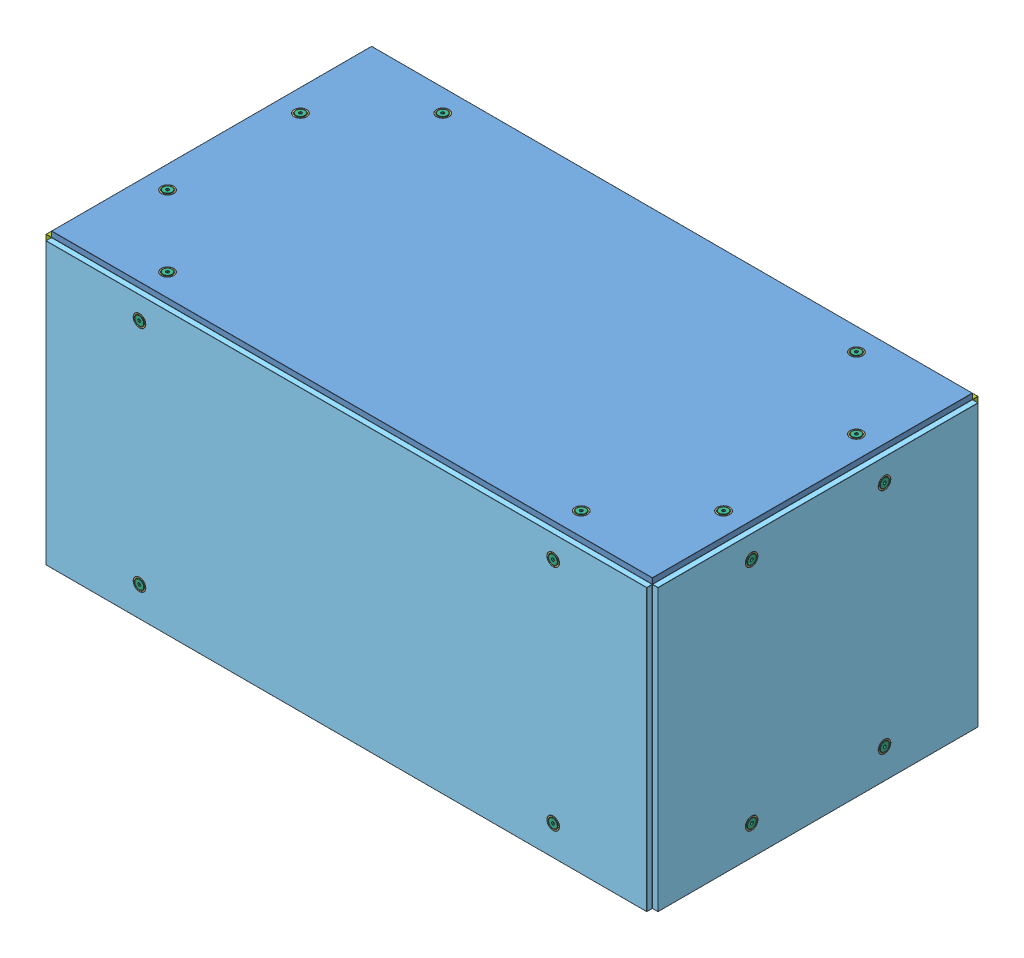
SolidWorks assembly SC.1.GD-VC, configuration Glass Dome 654 x 354 x 300. Lengths in mm.
Overall size (654.53 306.26 354.53).
109 component instances, 7 part files, 60 mates.
Components (placement in the parent):
- SC.1.G.VC.T-1: SC.1.G.VC.T [Topo 642 x 342] at (-2.0067 135.176 -92.8158) size (642 6 342)
- SC.1.L-1: SC.1.L [Default] at (-230.0067 117.676 60.6842) x (0 0 -1) z (1 0 0)
- SC.1.AC2-1: SC.1.AC2 [Default] at (-223.0067 136.176 54.1842) x (0 -1 0) z (0 0 1)
- SC.1.A2-1: SC.1.A2 [Default] at (-223.0067 133.176 54.1842) x (1 0 0) z (0 1 0)
- SC.1.A2-2: SC.1.A2 [Default] at (-223.0067 131.176 54.1842) x (1 0 0) z (0 1 0)
- SC.1.L-2: SC.1.L [Default] at (301.4933 117.676 -14.8158) x (-1 0 0) z (0 0 -1)
- SC.1.AC2-2: SC.1.AC2 [Default] at (294.9933 136.176 -21.8158) x (0 -1 0) z (0 0 1)
- SC.1.A2-3: SC.1.A2 [Default] at (294.9933 131.176 -21.8158) x (1 0 0) z (0 1 0)
- SC.1.A2-4: SC.1.A2 [Default] at (294.9933 133.176 -21.8158) x (1 0 0) z (0 1 0)
- SC.1.AC2-3: SC.1.AC2 [Default] at (218.9933 136.176 54.1842) x (0 -1 0) z (0 0 -1)
- SC.1.A2-5: SC.1.A2 [Default] at (218.9933 135.176 54.1842) x (-1 0 0) z (0 -1 0)
- SC.1.A2-6: SC.1.A2 [Default] at (218.9933 133.176 54.1842) x (-1 0 0) z (0 -1 0)
- SC.1.L-3: SC.1.L [Default] at (211.9933 117.676 60.6842) x (0 0 -1) z (1 0 0)
- SC.1.AC2-4: SC.1.AC2 [Default] at (294.9933 136.176 -163.8158) x (0 -1 0) z (0 0 1)
- SC.1.A2-7: SC.1.A2 [Default] at (294.9933 135.176 -163.8158) x (1 0 0) z (0 -1 0)
- SC.1.A2-8: SC.1.A2 [Default] at (294.9933 133.176 -163.8158) x (1 0 0) z (0 -1 0)
- SC.1.L-4: SC.1.L [Default] at (301.4933 117.676 -156.8158) x (-1 0 0) z (0 0 -1)
- SC.1.AC2-5: SC.1.AC2 [Default] at (-299.0067 136.176 -21.8158) x (0 -1 0) z (0 0 -1)
- SC.1.A2-9: SC.1.A2 [Default] at (-299.0067 135.176 -21.8158) x (-1 0 0) z (0 -1 0)
- SC.1.A2-10: SC.1.A2 [Default] at (-299.0067 133.176 -21.8158) x (-1 0 0) z (0 -1 0)
- SC.1.L-5: SC.1.L [Default] at (-305.5067 117.676 -28.8158)
- SC.1.AC2-6: SC.1.AC2 [Default] at (-299.0067 136.176 -163.8158) x (0 -1 0) z (0 0 -1)
- SC.1.A2-11: SC.1.A2 [Default] at (-299.0067 133.176 -163.8158) x (-1 0 0) z (0 1 0)
- SC.1.A2-12: SC.1.A2 [Default] at (-299.0067 131.176 -163.8158) x (-1 0 0) z (0 1 0)
- SC.1.L-6: SC.1.L [Default] at (-305.5067 117.676 -170.8158)
- SC.1.AC2-7: SC.1.AC2 [Default] at (218.9933 136.176 -239.8158) x (0 -1 0) z (0 0 -1)
- SC.1.A2-13: SC.1.A2 [Default] at (218.9933 133.176 -239.8158) x (-1 0 0) z (0 1 0)
- SC.1.A2-14: SC.1.A2 [Default] at (218.9933 131.176 -239.8158) x (-1 0 0) z (0 1 0)
- SC.1.L-7: SC.1.L [Default] at (225.9933 117.676 -246.3158) x (0 0 1) z (-1 0 0)
- SC.1.AC2-8: SC.1.AC2 [Default] at (-223.0067 136.176 -239.8158) x (0 -1 0) z (0 0 1)
- SC.1.A2-15: SC.1.A2 [Default] at (-223.0067 135.176 -239.8158) x (1 0 0) z (0 -1 0)
- SC.1.A2-16: SC.1.A2 [Default] at (-223.0067 133.176 -239.8158) x (1 0 0) z (0 -1 0)
- SC.1.L-8: SC.1.L [Default] at (-216.0067 117.676 -246.3158) x (0 0 1) z (-1 0 0)
- SC.1.A2-20: SC.1.A2 [Default] at (-223.0067 111.176 74.1842)
- SC.1.A2-21: SC.1.A2 [Default] at (-223.0067 111.176 76.1842)
- SC.1.G.VC.L-1: SC.1.G.VC.L [Lateral 642 x 300] at (-2.0067 -14.824 78.1842)
- SC.1.A2-22: SC.1.A2 [Default] at (316.9933 111.176 -21.8158) x (0 0 -1) z (1 0 0)
- SC.1.A2-23: SC.1.A2 [Default] at (314.9933 111.176 -21.8158) x (0 0 -1) z (1 0 0)
- SC.1.G.VC.L-5: SC.1.G.VC.L [Lateral 342 x 300] at (318.9933 -14.824 -92.8158) x (0 0 -1) z (1 0 0)
- SC.1.AC2-10: SC.1.AC2 [Default] at (-223.0067 111.176 79.1842) x (0 0 -1) z (0 -1 0)
- SC.1.AC2-11: SC.1.AC2 [Default] at (319.9933 111.176 -21.8158) x (-1 0 0) z (0 0 1)
- SC.1.P7991-12-1: SC.1.P7991-12 [ISO 10642 - M5 x 12 --- 12N] at (-223.0067 141.4402 54.1842) x (0 -1 0) z (0 0 1)
- SC.1.P7991-12-17: SC.1.P7991-12 [ISO 10642 - M5 x 12 --- 12N] at (-223.0067 111.176 84.4484) x (0 0 -1) z (0 -1 0)
- SC.1.P7991-12-21: SC.1.P7991-12 [ISO 10642 - M5 x 12 --- 12N] at (294.9933 141.4402 -21.8158) x (0 -1 0) z (0 0 1)
- SC.1.P7991-12-25: SC.1.P7991-12 [ISO 10642 - M5 x 12 --- 12N] at (325.2575 111.176 -21.8158) x (-1 0 0) z (0 0 1)
- SC.1.P7991-12-5: SC.1.P7991-12 [ISO 10642 - M5 x 12 --- 12N] at (218.9933 141.4402 54.1842) x (0 -1 0) z (0 0 -1)
- SC.1.P7991-12-18: SC.1.P7991-12 [ISO 10642 - M5 x 12 --- 12N] at (218.9933 111.176 84.4484) x (0 0 -1) z (0 1 0)
- SC.1.AC2-12: SC.1.AC2 [Default] at (218.9933 111.176 79.1842) x (0 0 -1) z (0 1 0)
- SC.1.A2-24: SC.1.A2 [Default] at (218.9933 111.176 78.1842) x (-1 0 0) z (0 0 -1)
- SC.1.A2-25: SC.1.A2 [Default] at (218.9933 111.176 76.1842) x (-1 0 0) z (0 0 -1)
- SC.1.P7991-12-22: SC.1.P7991-12 [ISO 10642 - M5 x 12 --- 12N] at (294.9933 141.4402 -163.8158) x (0 -1 0) z (0 0 1)
- SC.1.P7991-12-26: SC.1.P7991-12 [ISO 10642 - M5 x 12 --- 12N] at (325.2575 111.176 -163.8158) x (-1 0 0) z (0 0 1)
- SC.1.AC2-13: SC.1.AC2 [Default] at (319.9933 111.176 -163.8158) x (-1 0 0) z (0 0 1)
- SC.1.A2-26: SC.1.A2 [Default] at (318.9933 111.176 -163.8158) x (0 0 1) z (-1 0 0)
- SC.1.A2-27: SC.1.A2 [Default] at (316.9933 111.176 -163.8158) x (0 0 1) z (-1 0 0)
- SC.1.P7991-12-24: SC.1.P7991-12 [ISO 10642 - M5 x 12 --- 12N] at (-299.0067 141.4402 -21.8158) x (0 -1 0) z (0 0 -1)
- SC.1.A2-28: SC.1.A2 [Default] at (-323.0067 111.176 -21.8158) x (0 0 -1) z (1 0 0)
- SC.1.A2-29: SC.1.A2 [Default] at (-321.0067 111.176 -21.8158) x (0 0 -1) z (1 0 0)
- SC.1.AC2-14: SC.1.AC2 [Default] at (-324.0067 111.176 -21.8158) x (1 0 0) z (0 0 -1)
- SC.1.P7991-12-28: SC.1.P7991-12 [ISO 10642 - M5 x 12 --- 12N] at (-329.2709 111.176 -21.8158) x (1 0 0) z (0 0 -1)
- MirrorSC.1.G.VC.L-6: MirrorSC.1.G.VC.L [Lateral 342 x 300] at (-323.0067 -14.824 -92.8158) x (0 0 -1) z (1 0 0)
- SC.1.P7991-12-27: SC.1.P7991-12 [ISO 10642 - M5 x 12 --- 12N] at (-329.2709 111.176 -163.8158) x (1 0 0) z (0 0 -1)
- SC.1.AC2-15: SC.1.AC2 [Default] at (-324.0067 111.176 -163.8158) x (1 0 0) z (0 0 -1)
- SC.1.P7991-12-23: SC.1.P7991-12 [ISO 10642 - M5 x 12 --- 12N] at (-299.0067 141.4402 -163.8158) x (0 -1 0) z (0 0 -1)
- SC.1.P7991-12-20: SC.1.P7991-12 [ISO 10642 - M5 x 12 --- 12N] at (-223.0067 111.176 -270.08) x (0 0 1) z (0 1 0)
- SC.1.AC2-16: SC.1.AC2 [Default] at (-223.0067 111.176 -264.8158) x (0 0 1) z (0 1 0)
- SC.1.A2-30: SC.1.A2 [Default] at (-223.0067 111.176 -263.8158)
- SC.1.A2-31: SC.1.A2 [Default] at (-223.0067 111.176 -261.8158)
- SC.1.P7991-12-16: SC.1.P7991-12 [ISO 10642 - M5 x 12 --- 12N] at (-223.0067 141.4402 -239.8158) x (0 -1 0) z (0 0 1)
- SC.1.P7991-12-15: SC.1.P7991-12 [ISO 10642 - M5 x 12 --- 12N] at (218.9933 141.4402 -239.8158) x (0 -1 0) z (0 0 -1)
- SC.1.A2-32: SC.1.A2 [Default] at (218.9933 111.176 -261.8158) x (-1 0 0) z (0 0 -1)
- SC.1.A2-33: SC.1.A2 [Default] at (218.9933 111.176 -259.8158) x (-1 0 0) z (0 0 -1)
- SC.1.P7991-12-19: SC.1.P7991-12 [ISO 10642 - M5 x 12 --- 12N] at (218.9933 111.176 -270.08) x (0 0 1) z (0 -1 0)
- SC.1.AC2-17: SC.1.AC2 [Default] at (218.9933 111.176 -264.8158) x (0 0 1) z (0 -1 0)
- MirrorSC.1.G.VC.L-7: MirrorSC.1.G.VC.L [Lateral 642 x 300] at (-2.0067 -14.824 -263.8158)
- SC.1.P7991-12-29: SC.1.P7991-12 [ISO 10642 - M5 x 12 --- 12N] at (-223.0067 -132.824 84.4484) x (0 0 -1) z (0 -1 0)
- SC.1.AC2-18: SC.1.AC2 [Default] at (-223.0067 -132.824 79.1842) x (0 0 -1) z (0 -1 0)
- SC.1.A2-34: SC.1.A2 [Default] at (-223.0067 -132.824 74.1842)
- SC.1.A2-35: SC.1.A2 [Default] at (-223.0067 -132.824 76.1842)
- SC.1.P7991-12-33: SC.1.P7991-12 [ISO 10642 - M5 x 12 --- 12N] at (325.2575 -132.824 -21.8158) x (-1 0 0) z (0 0 1)
- SC.1.AC2-19: SC.1.AC2 [Default] at (319.9933 -132.824 -21.8158) x (-1 0 0) z (0 0 1)
- SC.1.A2-36: SC.1.A2 [Default] at (314.9933 -132.824 -21.8158) x (0 -1 0) z (1 0 0)
- SC.1.A2-37: SC.1.A2 [Default] at (316.9933 -132.824 -21.8158) x (0 -1 0) z (1 0 0)
- SC.1.P7991-12-30: SC.1.P7991-12 [ISO 10642 - M5 x 12 --- 12N] at (218.9933 -132.824 84.4484) x (0 0 -1) z (0 1 0)
- SC.1.AC2-20: SC.1.AC2 [Default] at (218.9933 -132.824 79.1842) x (0 0 -1) z (0 1 0)
- SC.1.A2-38: SC.1.A2 [Default] at (218.9933 -132.824 78.1842) x (-1 0 0) z (0 0 -1)
- SC.1.A2-39: SC.1.A2 [Default] at (218.9933 -132.824 76.1842) x (-1 0 0) z (0 0 -1)
- SC.1.P7991-12-34: SC.1.P7991-12 [ISO 10642 - M5 x 12 --- 12N] at (325.2575 -132.824 -163.8158) x (-1 0 0) z (0 0 1)
- SC.1.AC2-21: SC.1.AC2 [Default] at (319.9933 -132.824 -163.8158) x (-1 0 0) z (0 0 1)
- SC.1.A2-40: SC.1.A2 [Default] at (318.9933 -132.824 -163.8158) x (0 -1 0) z (-1 0 0)
- SC.1.A2-41: SC.1.A2 [Default] at (316.9933 -132.824 -163.8158) x (0 -1 0) z (-1 0 0)
- SC.1.P7991-12-36: SC.1.P7991-12 [ISO 10642 - M5 x 12 --- 12N] at (-329.2709 -132.824 -21.8158) x (1 0 0) z (0 0 -1)
- SC.1.AC2-22: SC.1.AC2 [Default] at (-324.0067 -132.824 -21.8158) x (1 0 0) z (0 0 -1)
- SC.1.P7991-12-35: SC.1.P7991-12 [ISO 10642 - M5 x 12 --- 12N] at (-329.2709 -132.824 -163.8158) x (1 0 0) z (0 0 -1)
- SC.1.AC2-23: SC.1.AC2 [Default] at (-324.0067 -132.824 -163.8158) x (1 0 0) z (0 0 -1)
- SC.1.A2-42: SC.1.A2 [Default] at (-321.0067 -132.824 -163.8158) x (0 -1 0) z (-1 0 0)
- SC.1.A2-43: SC.1.A2 [Default] at (-319.0067 -132.824 -163.8158) x (0 -1 0) z (-1 0 0)
- SC.1.A2-44: SC.1.A2 [Default] at (-323.0067 -132.824 -21.8158) x (0 -1 0) z (1 0 0)
- SC.1.A2-45: SC.1.A2 [Default] at (-321.0067 -132.824 -21.8158) x (0 -1 0) z (1 0 0)
- SC.1.A2-46: SC.1.A2 [Default] at (-321.0067 111.176 -163.8158) x (0 0 1) z (-1 0 0)
- SC.1.A2-47: SC.1.A2 [Default] at (-319.0067 111.176 -163.8158) x (0 0 1) z (-1 0 0)
- SC.1.AC2-24: SC.1.AC2 [Default] at (-223.0067 -132.824 -264.8158) x (0 0 1) z (0 1 0)
- SC.1.A2-48: SC.1.A2 [Default] at (-223.0067 -132.824 -263.8158)
- SC.1.A2-49: SC.1.A2 [Default] at (-223.0067 -132.824 -261.8158)
- SC.1.P7991-12-32: SC.1.P7991-12 [ISO 10642 - M5 x 12 --- 12N] at (-223.0067 -132.824 -270.08) x (0 0 1) z (0 1 0)
- SC.1.AC2-25: SC.1.AC2 [Default] at (218.9933 -132.824 -264.8158) x (0 0 1) z (0 -1 0)
- SC.1.A2-50: SC.1.A2 [Default] at (218.9933 -132.824 -261.8158) x (-1 0 0) z (0 0 -1)
- SC.1.A2-51: SC.1.A2 [Default] at (218.9933 -132.824 -259.8158) x (-1 0 0) z (0 0 -1)
- SC.1.P7991-12-31: SC.1.P7991-12 [ISO 10642 - M5 x 12 --- 12N] at (218.9933 -132.824 -270.08) x (0 0 1) z (0 -1 0)
Mates (geometry in assembly coordinates):
- Concentric3: concentric aligned: cylinder of SC.1.G.VC.T-1 through (-223.0067 135.176 54.1842) axis (0 1 0) radius 4; cylinder of SC.1.AC2-1 through (-223.0067 145.0904 54.1842) axis (0 1 0) radius 4
- Coincident2: coincident aligned: cone of SC.1.G.VC.T-1 through (-223.0067 138.426 54.1842) axis (0 -1 0); cone of SC.1.AC2-1 through (-223.0067 138.426 54.1842) axis (0 -1 0)
- Coincident3: coincident anti-aligned: plane of SC.1.G.VC.T-1 through (-2.0067 135.176 -92.8158) normal (0 -1 0); plane of SC.1.A2-1 through (-223.0067 135.176 54.1842) normal (0 1 0)
- Concentric5: concentric anti-aligned: cylinder of SC.1.AC2-1 through (-223.0067 145.0904 54.1842) axis (0 1 0) radius 4; cylinder of SC.1.A2-1 through (-223.0067 135.176 54.1842) axis (0 -1 0) radius 4
- Coincident4: coincident anti-aligned: plane of SC.1.A2-1 through (-223.0067 133.176 54.1842) normal (0 -1 0); plane of SC.1.A2-2 through (-223.0067 133.176 54.1842) normal (0 1 0)
- Concentric6: concentric anti-aligned: cylinder of SC.1.AC2-1 through (-223.0067 145.0904 54.1842) axis (0 1 0) radius 4; cylinder of SC.1.A2-2 through (-223.0067 133.176 54.1842) axis (0 -1 0) radius 4
- Coincident5: coincident anti-aligned: plane of SC.1.L-1 through (-216.0067 131.176 47.1842) normal (0 1 0); plane of SC.1.A2-2 through (-223.0067 131.176 54.1842) normal (0 -1 0)
- Concentric7: concentric aligned: cylinder of SC.1.L-1 through (-223.0067 131.176 54.1842) axis (0 1 0) radius 2.1; cylinder of SC.1.AC2-1 through (-223.0067 145.0904 54.1842) axis (0 1 0) radius 4
- Parallel1: parallel aligned: plane of SC.1.G.VC.T-1 through (-323.0067 141.176 78.1842) normal (0 0 1); plane of SC.1.L-1 through (-216.0067 131.176 74.1842) normal (0 0 1)
- Concentric8: concentric anti-aligned: cylinder of SC.1.AC2-2 through (294.9933 145.0904 -21.8158) axis (0 1 0) radius 4; cylinder of SC.1.A2-4 through (294.9933 135.176 -21.8158) axis (0 -1 0) radius 4
- Coincident7: coincident anti-aligned: plane of SC.1.A2-3 through (294.9933 133.176 -21.8158) normal (0 1 0); plane of SC.1.A2-4 through (294.9933 133.176 -21.8158) normal (0 -1 0)
- Concentric9: concentric anti-aligned: cylinder of SC.1.AC2-2 through (294.9933 145.0904 -21.8158) axis (0 1 0) radius 4; cylinder of SC.1.A2-3 through (294.9933 133.176 -21.8158) axis (0 -1 0) radius 4
- Coincident8: coincident anti-aligned: plane of SC.1.L-2 through (287.9933 131.176 -28.8158) normal (0 1 0); plane of SC.1.A2-3 through (294.9933 131.176 -21.8158) normal (0 -1 0)
- Concentric10: concentric aligned: cylinder of SC.1.L-2 through (294.9933 131.176 -21.8158) axis (0 1 0) radius 2.1; cylinder of SC.1.AC2-2 through (294.9933 145.0904 -21.8158) axis (0 1 0) radius 4
- Concentric11: concentric aligned: cylinder of SC.1.G.VC.T-1 through (294.9933 135.176 -21.8158) axis (0 1 0) radius 4; cylinder of SC.1.AC2-2 through (294.9933 145.0904 -21.8158) axis (0 1 0) radius 4
- Coincident9: coincident aligned: cone of SC.1.G.VC.T-1 through (294.9933 138.426 -21.8158) axis (0 -1 0); cone of SC.1.AC2-2 through (294.9933 138.426 -21.8158) axis (0 -1 0)
- Coincident10: coincident anti-aligned: plane of SC.1.G.VC.T-1 through (-2.0067 135.176 -92.8158) normal (0 -1 0); plane of SC.1.A2-4 through (294.9933 135.176 -21.8158) normal (0 1 0)
- Parallel2: parallel aligned: plane of SC.1.G.VC.T-1 through (318.9933 141.176 -263.8158) normal (1 0 0); plane of SC.1.L-2 through (314.9933 131.176 -28.8158) normal (1 0 0)
- Coincident15: coincident anti-aligned: plane of SC.1.L-1 through (-216.0067 131.176 74.1842) normal (0 0 1); plane of SC.1.A2-20 through (-223.0067 111.176 74.1842) normal (0 0 -1)
- Concentric14: concentric anti-aligned: cylinder of SC.1.L-1 through (-223.0067 111.176 74.1842) axis (0 0 1) radius 2.1; cylinder of SC.1.A2-20 through (-223.0067 111.176 76.1842) axis (0 0 -1) radius 4
- Coincident16: coincident anti-aligned: plane of SC.1.A2-20 through (-223.0067 111.176 76.1842) normal (0 0 1); plane of SC.1.A2-21 through (-223.0067 111.176 76.1842) normal (0 0 -1)
- Concentric15: concentric aligned: cylinder of SC.1.A2-20 through (-223.0067 111.176 76.1842) axis (0 0 -1) radius 4; cylinder of SC.1.A2-21 through (-223.0067 111.176 78.1842) axis (0 0 -1) radius 4
- Coincident17: coincident anti-aligned: plane of SC.1.A2-21 through (-223.0067 111.176 78.1842) normal (0 0 1); plane of SC.1.G.VC.L-1 through (-2.0067 -14.824 78.1842) normal (0 0 -1)
- Concentric16: concentric aligned: cylinder of SC.1.L-1 through (-223.0067 111.176 74.1842) axis (0 0 1) radius 2.1; cylinder of SC.1.G.VC.L-1 through (-223.0067 111.176 78.1842) axis (0 0 1) radius 4
- Concentric17: concentric aligned: cylinder of SC.1.L-3 through (218.9933 111.176 74.1842) axis (0 0 1) radius 2.1; cylinder of SC.1.G.VC.L-1 through (218.9933 111.176 78.1842) axis (0 0 1) radius 4
- Coincident18: coincident anti-aligned: plane of SC.1.A2-22 through (316.9933 111.176 -21.8158) normal (-1 0 0); plane of SC.1.A2-23 through (316.9933 111.176 -21.8158) normal (1 0 0)
- Concentric18: concentric aligned: cylinder of SC.1.A2-22 through (318.9933 111.176 -21.8158) axis (-1 0 0) radius 4; cylinder of SC.1.A2-23 through (316.9933 111.176 -21.8158) axis (-1 0 0) radius 4
- Coincident19: coincident anti-aligned: plane of SC.1.L-2 through (314.9933 131.176 -28.8158) normal (1 0 0); plane of SC.1.A2-23 through (314.9933 111.176 -21.8158) normal (-1 0 0)
- Concentric19: concentric anti-aligned: cylinder of SC.1.L-2 through (314.9933 111.176 -21.8158) axis (1 0 0) radius 2.1; cylinder of SC.1.A2-23 through (316.9933 111.176 -21.8158) axis (-1 0 0) radius 4
- Coincident20: coincident anti-aligned: plane of SC.1.A2-22 through (318.9933 111.176 -21.8158) normal (1 0 0); plane of SC.1.G.VC.L-5 through (318.9933 -14.824 -92.8158) normal (-1 0 0)
- Concentric20: concentric aligned: cylinder of SC.1.L-2 through (314.9933 111.176 -21.8158) axis (1 0 0) radius 2.1; cylinder of SC.1.G.VC.L-5 through (318.9933 111.176 -21.8158) axis (1 0 0) radius 4
- Concentric21: concentric aligned: cylinder of SC.1.L-4 through (314.9933 111.176 -163.8158) axis (1 0 0) radius 2.1; cylinder of SC.1.G.VC.L-5 through (318.9933 111.176 -163.8158) axis (1 0 0) radius 4
- Concentric22: concentric aligned: cylinder of SC.1.G.VC.L-1 through (-223.0067 111.176 78.1842) axis (0 0 1) radius 4; cylinder of SC.1.AC2-10 through (-223.0067 111.176 88.0987) axis (0 0 1) radius 4
- Coincident21: coincident aligned: cone of SC.1.G.VC.L-1 through (-223.0067 111.176 81.4342) axis (0 0 -1); cone of SC.1.AC2-10 through (-223.0067 111.176 81.4342) axis (0 0 -1)
- Concentric23: concentric aligned: cylinder of SC.1.G.VC.L-5 through (318.9933 111.176 -21.8158) axis (1 0 0) radius 4; cylinder of SC.1.AC2-11 through (328.9077 111.176 -21.8158) axis (1 0 0) radius 4
- Coincident22: coincident aligned: cone of SC.1.G.VC.L-5 through (322.2433 111.176 -21.8158) axis (-1 0 0); cone of SC.1.AC2-11 through (322.2433 111.176 -21.8158) axis (-1 0 0)
- Concentric24: concentric aligned: cylinder of SC.1.P7991-12-1 through (-223.0067 141.4402 54.1842) axis (0 1 0) radius 2.5; cylinder of SC.1.AC2-1 through (-223.0067 145.0904 54.1842) axis (0 1 0) radius 4
- Coincident23: coincident aligned: cone of SC.1.AC2-1 through (-223.0067 141.176 54.1842) axis (0 -1 0); cone of SC.1.P7991-12-1 through (-223.0067 140.5552 54.1842) axis (0 -1 0)
- Concentric26: concentric aligned: cylinder of SC.1.AC2-10 through (-223.0067 111.176 88.0987) axis (0 0 1) radius 4; cylinder of SC.1.P7991-12-17 through (-223.0067 111.176 84.4484) axis (0 0 1) radius 2.5
- Coincident24: coincident aligned: cone of SC.1.AC2-10 through (-223.0067 111.176 84.1842) axis (0 0 -1); cone of SC.1.P7991-12-17 through (-223.0067 111.176 83.5634) axis (0 0 -1)
- Concentric27: concentric aligned: cylinder of SC.1.AC2-2 through (294.9933 145.0904 -21.8158) axis (0 1 0) radius 4; cylinder of SC.1.P7991-12-21 through (294.9933 141.4402 -21.8158) axis (0 1 0) radius 2.5
- Coincident25: coincident aligned: cone of SC.1.AC2-2 through (294.9933 141.176 -21.8158) axis (0 -1 0); cone of SC.1.P7991-12-21 through (294.9933 140.5552 -21.8158) axis (0 -1 0)
- Concentric28: concentric aligned: cylinder of SC.1.AC2-11 through (328.9077 111.176 -21.8158) axis (1 0 0) radius 4; cylinder of SC.1.P7991-12-25 through (325.2575 111.176 -21.8158) axis (1 0 0) radius 2.5
- Coincident26: coincident aligned: cone of SC.1.AC2-11 through (324.9933 111.176 -21.8158) axis (-1 0 0); cone of SC.1.P7991-12-25 through (324.3725 111.176 -21.8158) axis (-1 0 0)
- Concentric29: concentric anti-aligned: cylinder of SC.1.AC2-18 through (-223.0067 -132.824 88.0987) axis (0 0 1) radius 4; cylinder of SC.1.A2-35 through (-223.0067 -132.824 78.1842) axis (0 0 -1) radius 4
- Coincident27: coincident anti-aligned: plane of SC.1.A2-34 through (-223.0067 -132.824 76.1842) normal (0 0 1); plane of SC.1.A2-35 through (-223.0067 -132.824 76.1842) normal (0 0 -1)
- Concentric30: concentric anti-aligned: cylinder of SC.1.AC2-18 through (-223.0067 -132.824 88.0987) axis (0 0 1) radius 4; cylinder of SC.1.A2-34 through (-223.0067 -132.824 76.1842) axis (0 0 -1) radius 4
- Concentric31: concentric aligned: cylinder of SC.1.P7991-12-29 through (-223.0067 -132.824 84.4484) axis (0 0 1) radius 2.5; cylinder of SC.1.AC2-18 through (-223.0067 -132.824 88.0987) axis (0 0 1) radius 4
- Coincident28: coincident aligned: cone of SC.1.P7991-12-29 through (-223.0067 -132.824 83.5634) axis (0 0 -1); cone of SC.1.AC2-18 through (-223.0067 -132.824 84.1842) axis (0 0 -1)
- Concentric32: concentric aligned: cylinder of SC.1.G.VC.L-1 through (-223.0067 -132.824 78.1842) axis (0 0 1) radius 4; cylinder of SC.1.AC2-18 through (-223.0067 -132.824 88.0987) axis (0 0 1) radius 4
- Coincident29: coincident aligned: cone of SC.1.G.VC.L-1 through (-223.0067 -132.824 81.4342) axis (0 0 -1); cone of SC.1.AC2-18 through (-223.0067 -132.824 81.4342) axis (0 0 -1)
- Coincident30: coincident anti-aligned: plane of SC.1.G.VC.L-1 through (-2.0067 -14.824 78.1842) normal (0 0 -1); plane of SC.1.A2-35 through (-223.0067 -132.824 78.1842) normal (0 0 1)
- Concentric33: concentric anti-aligned: cylinder of SC.1.AC2-19 through (328.9077 -132.824 -21.8158) axis (1 0 0) radius 4; cylinder of SC.1.A2-37 through (318.9933 -132.824 -21.8158) axis (-1 0 0) radius 4
- Coincident31: coincident anti-aligned: plane of SC.1.A2-36 through (316.9933 -132.824 -21.8158) normal (1 0 0); plane of SC.1.A2-37 through (316.9933 -132.824 -21.8158) normal (-1 0 0)
- Concentric34: concentric anti-aligned: cylinder of SC.1.AC2-19 through (328.9077 -132.824 -21.8158) axis (1 0 0) radius 4; cylinder of SC.1.A2-36 through (316.9933 -132.824 -21.8158) axis (-1 0 0) radius 4
- Concentric35: concentric aligned: cylinder of ? through (324.6968 -132.824 -21.8158) axis (1 0 0) radius 2.5; cylinder of SC.1.AC2-19 through (328.9077 -132.824 -21.8158) axis (1 0 0) radius 4
- Coincident32: coincident aligned: cone of SC.1.P7991-12-33 through (324.3725 -132.824 -21.8158) axis (-1 0 0); cone of SC.1.AC2-19 through (324.9933 -132.824 -21.8158) axis (-1 0 0)
- Concentric36: concentric aligned: cylinder of SC.1.G.VC.L-5 through (318.9933 -132.824 -21.8158) axis (1 0 0) radius 4; cylinder of SC.1.AC2-19 through (328.9077 -132.824 -21.8158) axis (1 0 0) radius 4
- Coincident33: coincident aligned: cone of SC.1.G.VC.L-5 through (322.2433 -132.824 -21.8158) axis (-1 0 0); cone of SC.1.AC2-19 through (322.2433 -132.824 -21.8158) axis (-1 0 0)
- Coincident34: coincident anti-aligned: plane of SC.1.G.VC.L-5 through (318.9933 -14.824 -92.8158) normal (-1 0 0); plane of SC.1.A2-37 through (318.9933 -132.824 -21.8158) normal (1 0 0)
